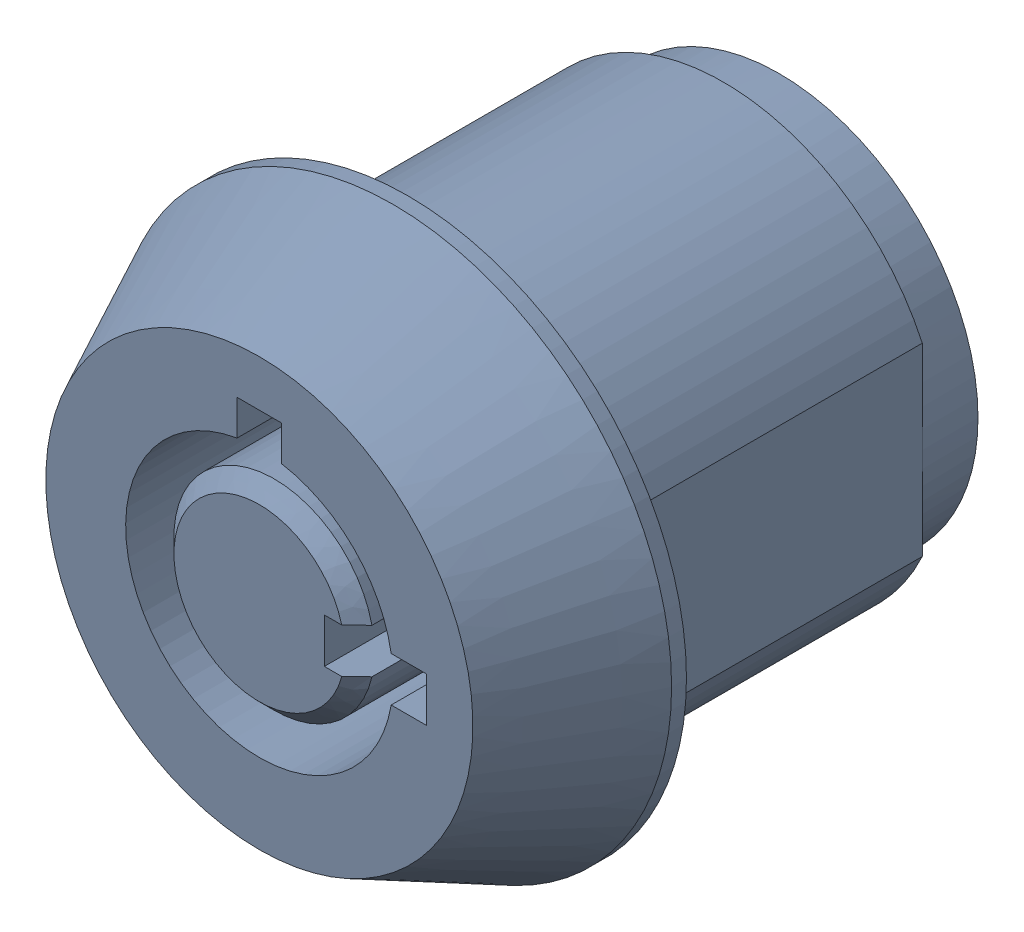
SolidWorks assembly Lock Assy(Default)-2, configuration Default. Lengths in mm.
Overall size (15 15 15.5).
2 component instances, 1 part files, 0 mates.
Components (placement in the parent):
- Lock - 10220022001-2-1: Lock - 10220022001-2 [Default] at (0 0 7.5) x (-1 0 0) z (0 0 -1) size (15 15 15.5)
  - Lock Body - 10220022001-2-1: Lock Body - 10220022001-2 [Default] x (-1 0 0) z (0 0 1) size (15 15 15.5)
